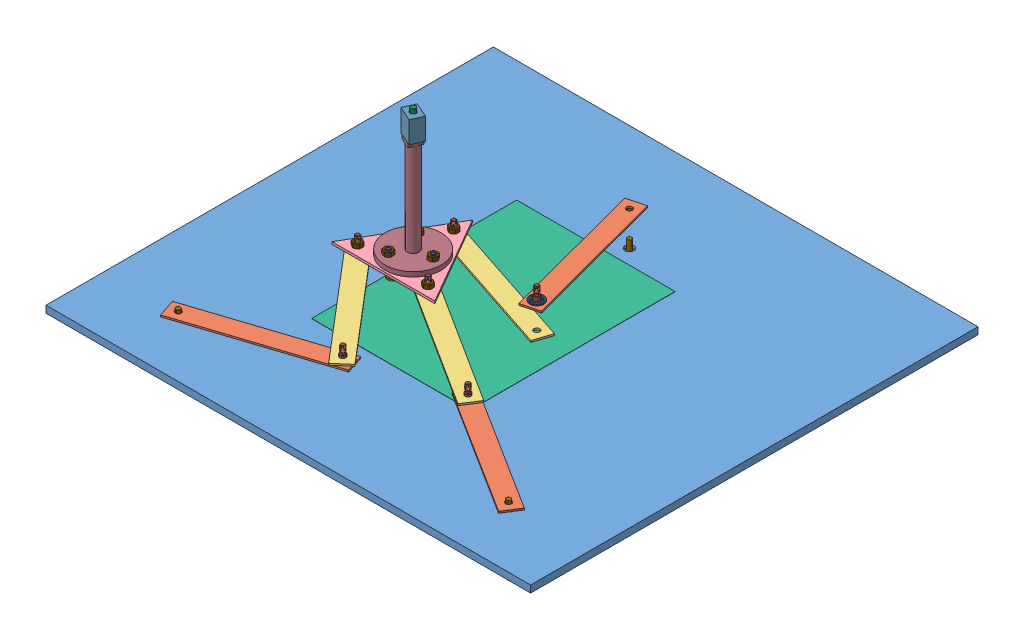
SolidWorks assembly 10_Full_3R_Assembly_rev3, configuration Default. Lengths in mm.
Overall size (660.4 267.78 609.6).
51 component instances, 18 part files, 122 mates.
Components (placement in the parent):
- 01_Base_Plate_rev3-1: 01_Base_Plate_rev3 [Default] at (-311.7855 -6.35 287.7555) size (660.4 9.53 609.6)
- 02_A_Link-1: 02_A_Link [Default] at (-214.7222 8.3926 228.6505) x (0.950724 0 -0.310038) z (0.310038 0 0.950724) size (203.2 2.29 25.4)
- 03_B_Link-1: 03_B_Link [Default] at (-19.6437 12.663 158.9505) x (-0.648292 0 -0.761391) z (0.761391 0 -0.648292) size (203.2 2.29 25.4)
- 02_A_Link-2: 02_A_Link [Default] at (75.596 8.3926 121.5978) x (0.84532 0 0.53426) z (-0.53426 0 0.84532) size (203.2 2.29 25.4)
- 03_B_Link-2: 03_B_Link [Default] at (-74.3873 12.663 26.0288) x (0.843475 0 0.537169) z (-0.537169 0 0.843475) size (203.2 2.29 25.4)
- 02_A_Link-3: 02_A_Link [Default] at (27.4339 49.9469 -192.6042) x (0.25639 0 0.966573) z (0.966573 0 -0.25639) size (203.2 2.29 25.4)
- 03_B_Link-3: 03_B_Link [Default] at (-120.8748 12.663 -52.8875) x (0.949572 0 0.31355) z (-0.31355 0 0.949572) size (203.2 2.29 25.4)
- 04_Platform-1: 04_Platform [Default] at (-174.8101 16.9333 34.8387) size (139.95 3.17 121.2)
- 05_Pen-1: 05_Pen [Default] at (-104.8331 21.9604 -5.5625) x (-0.946735 0 0.322013) z (-0.322013 0 -0.946735) size (12.7 123.83 12.7)
- 06_Paper-1: 06_Paper [Default] at (-114.9356 3.175 122.6553) size (215.9 0.25 279.4)
- 10_Ball_Transfer-1: 10_Ball_Transfer [Default] at (-100.4832 13.2803 -30.5665) x (0.999999 0 0.001404) z (0.001404 0 -0.999999) size (14.51 13.76 14.51)
  - 09_Ball_Holder-1: 09_Ball_Holder [Default] at (19.6556 -3.653 -11.1258) size (14.51 9.53 14.51)
  - 08_Ball-1: 08_Ball [Default] at (19.6556 5.872 -11.1258) size (8.47 8.47 8.47)
- 10_Ball_Transfer-2: 10_Ball_Transfer [Default] at (-82.2518 13.2803 22.5984) x (-0.880102 0 0.474785) z (0.474785 0 0.880102) size (14.51 13.76 14.51)
  - 09_Ball_Holder-1: 09_Ball_Holder [Default] at (19.6556 -3.653 -11.1258) size (14.51 9.53 14.51)
  - 08_Ball-1: 08_Ball [Default] at (19.6556 5.872 -11.1258) size (8.47 8.47 8.47)
- 10_Ball_Transfer-3: 10_Ball_Transfer [Default] at (-148.0473 13.5343 -31.2689) x (0.999295 0 0.037538) z (0.037538 0 -0.999295) size (14.51 13.76 14.51)
  - 09_Ball_Holder-1: 09_Ball_Holder [Default] at (19.6556 -3.653 -11.1258) size (14.51 9.53 14.51)
  - 08_Ball-1: 08_Ball [Default] at (19.6556 5.872 -11.1258) size (8.47 8.47 8.47)
- 07_Motor_rev2-1: 07_Motor_rev2 [Default] at (14.4968 -74.05 -182.8736) x (0 -1 0) z (-0.828709 0 0.559679) size (88.7 37 37)
- 07_Motor_rev2-2: 07_Motor_rev2 [Default] at (-213.4691 -74.05 211.368) x (0 -1 0) z (-0.181552 0 0.983381) size (88.7 37 37)
- 07_Motor_rev2-3: 07_Motor_rev2 [Default] at (250.3675 -74.05 211.8284) x (0 -1 0) z (-0.115781 0 -0.993275) size (88.7 37 37)
- 5909K24_Needle-Roller Thrust Bearing-1: 5909K24_Needle-Roller Thrust Bearing [5909K24] at (64.0007 50.9391 -5.2159) x (-0.973754 0 -0.227603) z (0.227603 0 -0.973754) size (19.05 1.98 19.05)
- 91259A576_Alloy Steel Shoulder Screw-1: 91259A576_Alloy Steel Shoulder Screw [91259A576] at (64.0007 42.1046 -5.2159) x (0.154475 0 0.987997) z (0 -1 0) size (11.11 11.11 26.95)
- 5909K24_Needle-Roller Thrust Bearing-3: 5909K24_Needle-Roller Thrust Bearing [5909K24] at (-37.5467 11.6708 157.5141) x (0.9423 0 0.334769) z (-0.334769 0 0.9423) size (19.05 1.98 19.05)
- 5909K24_Needle-Roller Thrust Bearing-4: 5909K24_Needle-Roller Thrust Bearing [5909K24] at (93.1166 11.6708 117.6473) x (0.999962 0 -0.008701) z (0.008701 0 0.999962) size (19.05 1.98 19.05)
- 91259A576_Alloy Steel Shoulder Screw-2: 91259A576_Alloy Steel Shoulder Screw [91259A576] at (-37.5467 2.8363 157.5141) x (0.890655 0 -0.45468) z (0 -1 0) size (11.11 11.11 26.95)
- 91259A576_Alloy Steel Shoulder Screw-3: 91259A576_Alloy Steel Shoulder Screw [91259A576] at (93.1166 2.8363 117.6473) x (0.621536 0 -0.783386) z (0 -1 0) size (11.11 11.11 26.95)
- 91259A576_Alloy Steel Shoulder Screw-4: 91259A576_Alloy Steel Shoulder Screw [91259A576] at (-152.8131 7.1067 22.1387) x (-0.287715 0 -0.957716) z (0 -1 0) size (11.11 11.11 26.95)
- 91259A576_Alloy Steel Shoulder Screw-5: 91259A576_Alloy Steel Shoulder Screw [91259A576] at (-56.8532 7.1067 22.1387) x (0.554326 0 -0.8323) z (0 -1 0) size (11.11 11.11 26.95)
- 91259A576_Alloy Steel Shoulder Screw-6: 91259A576_Alloy Steel Shoulder Screw [91259A576] at (-104.8331 7.1067 -60.965) x (0.999981 0 0.006147) z (0 -1 0) size (11.11 11.11 26.95)
- 5909K24_Needle-Roller Thrust Bearing-5: 5909K24_Needle-Roller Thrust Bearing [5909K24] at (-152.8131 15.9411 22.1387) x (0.997045 0 0.076824) z (-0.076824 0 0.997045) size (19.05 1.98 19.05)
- 5909K24_Needle-Roller Thrust Bearing-6: 5909K24_Needle-Roller Thrust Bearing [5909K24] at (-104.8331 15.9411 -60.965) x (0.994154 0 -0.107968) z (0.107968 0 0.994154) size (19.05 1.98 19.05)
- 5909K24_Needle-Roller Thrust Bearing-7: 5909K24_Needle-Roller Thrust Bearing [5909K24] at (-56.8532 15.9411 22.1387) x (0.969179 0 -0.246358) z (0.246358 0 0.969179) size (19.05 1.98 19.05)
- 6056N14_Carbon Steel Set Screw Collar-1: 6056N14_Carbon Steel Set Screw Collar [6056N14] at (-206.5855 4.3926 212.6388) x (-0.584369 0 0.811488) z (0 1 0) size (12 12.47 8)
- 6056N14_Carbon Steel Set Screw Collar-2: 6056N14_Carbon Steel Set Screw Collar [6056N14] at (18.4145 43.6609 -177.0726) x (0.948137 0 -0.317863) z (0 1 0) size (12 12.47 8)
- 6056N14_Carbon Steel Set Screw Collar-3: 6056N14_Carbon Steel Set Screw Collar [6056N14] at (243.4145 4.3926 212.6388) x (0.999426 0 0.033886) z (0 -1 0) size (12 12.47 8)
- PenHolder-1: PenHolder [Default] at (-104.8331 20.1083 -5.5625) x (-0.407207 0 0.913336) z (-0.913336 0 -0.407207) size (76.2 138.35 76.2)
- SolenoidAssembly-1: SolenoidAssembly [Default] at (-66.5015 141.5889 -4.966) x (-0.407207 0 0.913336) z (-0.913336 0 -0.407207) size (17 55.9 22)
  - Solenoid_Mount-2: Solenoid_Mount [Default] at (6.5641 46.5695 46.2525) x (1 0 0) z (0 0 -1) size (17 29.7 22)
  - Solenoid_Shaft-1: Solenoid_Shaft [Default] at (15.0641 0.2373 35.2525) x (-0.773677 0 0.63358) z (-0.63358 0 -0.773677) size (6.9 51.9 6.9)
  - Solenoid_Cap-1: Solenoid_Cap [Default] at (15.0641 -3.7627 35.2525) x (0.200587 0 -0.979676) z (0.979676 0 0.200587) size (5 12 5)
- 90604A539_Pan Head Combination Phillips Slotted Screws-1: 90604A539_Pan Head Combination Phillips Slotted Screws [90604A539] at (-119.336 32.8083 -26.415) x (-0.886591 0 -0.462554) z (0 -1 0) size (12.5 12.5 20.66)
- 90604A539_Pan Head Combination Phillips Slotted Screws-2: 90604A539_Pan Head Combination Phillips Slotted Screws [90604A539] at (-115.6405 32.8083 17.4236) x (0.746863 0 0.664978) z (0 -1 0) size (12.5 12.5 20.66)
- 90604A539_Pan Head Combination Phillips Slotted Screws-3: 90604A539_Pan Head Combination Phillips Slotted Screws [90604A539] at (-79.5229 32.8083 -7.696) x (1 0 0) z (0 -1 0) size (12.5 12.5 20.66)
- 95462A029_Medium-Strength Steel Hex Nut-1: 95462A029_Medium-Strength Steel Hex Nut [95462A029] at (-79.5229 29.2365 -7.696) x (-0.145713 0 -0.989327) z (0 -1 0) size (11.11 12.83 6.51)
- 95462A029_Medium-Strength Steel Hex Nut-2: 95462A029_Medium-Strength Steel Hex Nut [95462A029] at (-56.8532 22.8865 22.1387) x (-1 0 0) z (0 1 0) size (11.11 12.83 6.51)
- 95462A029_Medium-Strength Steel Hex Nut-3: 95462A029_Medium-Strength Steel Hex Nut [95462A029] at (-119.336 29.2365 -26.415) x (-1 0 0) z (0 1 0) size (11.11 12.83 6.51)
- 95462A029_Medium-Strength Steel Hex Nut-4: 95462A029_Medium-Strength Steel Hex Nut [95462A029] at (-152.8131 22.8865 22.1387) x (-1 0 0) z (0 1 0) size (11.11 12.83 6.51)
- 95462A029_Medium-Strength Steel Hex Nut-5: 95462A029_Medium-Strength Steel Hex Nut [95462A029] at (-104.8331 22.8865 -60.965) x (-1 0 0) z (0 1 0) size (11.11 12.83 6.51)
- 95462A029_Medium-Strength Steel Hex Nut-6: 95462A029_Medium-Strength Steel Hex Nut [95462A029] at (-115.6405 29.2365 17.4236) x (-0.377684 0 0.925934) z (0 -1 0) size (11.11 12.83 6.51)
Mates (geometry in assembly coordinates):
- Concentric4: concentric anti-aligned: circle of 04_Platform-1; circle of 05_Pen-1
- Coincident21: coincident anti-aligned: plane of 01_Base_Plate_rev3-1 through (-311.7855 3.175 287.7555) normal (0 1 0); plane of 06_Paper-1 through (-114.9356 3.175 122.6553) normal (0 -1 0)
- Distance1: distance = 196.85 mm: line of 06_Paper-1 through (-114.9356 3.429 -156.7447) axis (0 0 1); line of 01_Base_Plate_rev3-1 through (-311.7855 3.175 -321.8445) axis (0 0 1)
- Distance2: distance = 165.1 mm: line of 06_Paper-1 through (100.9644 3.429 -156.7447) axis (-1 0 0); line of 01_Base_Plate_rev3-1 through (348.6145 3.175 -321.8445) axis (-1 0 0)
- Tangent1: tangent anti-aligned: plane of 06_Paper-1 through (-114.9356 3.429 122.6553) normal (0 1 0); sphere of 08_Roller-1
- Tangent2: tangent anti-aligned: plane of 06_Paper-1 through (-114.9356 3.429 122.6553) normal (0 1 0); sphere of 08_Roller-2
- Tangent3: tangent anti-aligned: plane of 06_Paper-1 through (-114.9356 3.429 122.6553) normal (0 1 0); sphere of 08_Roller-3
- Tangent4: tangent anti-aligned: plane of 04_Platform-1 through (-174.8101 16.9333 34.8387) normal (0 -1 0); sphere of 08_Roller-1
- Coincident37: coincident anti-aligned: plane of 02_A_Link-3 through (27.4339 47.6609 -192.6042) normal (0 -1 0); plane of 07_Motor-3 through (15.6523 48.5738 -175.9022) normal (0 1 0)
- Concentric8: concentric aligned: circle of 02_A_Link-3; circle of 07_Motor-3
- Parallel3: parallel aligned: plane of 01_Base_Plate_rev3-1 through (-311.7855 3.175 287.7555) normal (0 0 1); plane of 04_Platform-1 through (-174.8101 20.1083 34.8387) normal (0 0 1)
- Concentric10: concentric anti-aligned: circle of 04_Platform-1; circle of 10_Ball_Transfer-1/09_Ball_Holder-1
- Concentric11: concentric anti-aligned: circle of 04_Platform-1; circle of 10_Ball_Transfer-3/09_Ball_Holder-1
- Concentric12: concentric anti-aligned: circle of 04_Platform-1; circle of 10_Ball_Transfer-2/09_Ball_Holder-1
- Concentric23: concentric anti-aligned: circle of 02_A_Link-1; circle of 07_Motor_rev2-2
- Concentric24: concentric anti-aligned: circle of 02_A_Link-2; circle of 07_Motor_rev2-3
- Concentric25: concentric aligned: circle of 02_A_Link-3; circle of 07_Motor_rev2-1
- Tangent5: tangent anti-aligned: plane of 01_Base_Plate_rev3-1 through (-311.7855 3.175 287.7555) normal (0 1 0); sphere of 10_Ball_Transfer-1/08_Ball-1
- Coincident51: coincident anti-aligned: plane of 01_Base_Plate_rev3-1 through (-311.7855 -6.35 287.7555) normal (0 -1 0); plane of Motor_Mount-1 through (2.2171 -6.35 -164.284) normal (0 1 0)
- Concentric26: concentric anti-aligned: cylinder of 07_Motor_rev2-1 through (14.4968 6.0614 -182.8736) axis (0 1 0) radius 18.5; cylinder of Motor_Mount-1 through (18.4145 -100.9975 -177.0726) axis (0 -1 0) radius 20.6375
- Concentric29: concentric aligned: cylinder of 03_B_Link-3 through (64.0007 12.663 -5.2159) axis (0 1 0) radius 3.9688; cylinder of 91259A427_Alloy Steel Shoulder Screw-1 through (-164.7374 27.7812 -154.398) axis (0 1 0) radius 3.9688
- Concentric30: concentric aligned: cylinder of 02_A_Link-3 through (64.0007 49.9469 -5.2159) axis (0 -1 0) radius 3.9688; cylinder of 5909K24_Needle-Roller Thrust Bearing-1 through (64.0007 49.9469 -5.2159) axis (0 -1 0) radius 3.9624
- Tangent7: tangent anti-aligned: plane of 02_A_Link-3 through (27.4339 49.9469 -192.6042) normal (0 1 0); cylinder of 5909K24_Needle-Roller Thrust Bearing-1 through (70.4402 50.9391 0.8219) axis (0.729494 0 0.683987) radius 0.9922
- Coincident58: coincident anti-aligned: plane of 07_Motor_rev2-1 through (24.1513 -28.25 -168.5783) normal (0 -1 0); plane of Motor_Mount-1 through (3.4631 -22.225 -165.2677) normal (0 1 0)
- Coincident61: coincident anti-aligned: plane of 01_Base_Plate_rev3-1 through (-311.7855 3.175 287.7555) normal (0 1 0); plane of 91259A427_Alloy Steel Shoulder Screw-1 through (-164.7374 6.35 -154.398) normal (0 -1 0)
- Concentric32: concentric anti-aligned: cylinder of 02_A_Link-3 through (64.0007 49.9469 -5.2159) axis (0 -1 0) radius 3.9688; cylinder of 03_B_Link-3 through (64.0007 12.663 -5.2159) axis (0 1 0) radius 3.9688
- Concentric33: concentric anti-aligned: circle of 03_B_Link-3; circle of 5909K24_Needle-Roller Thrust Bearing-2
- Tangent10: tangent anti-aligned: plane of 5909K24_Needle-Roller Thrust Bearing-1 through (66.1687 51.4352 -14.4909) normal (0 1 0); cylinder of 5909K24_Needle-Roller Thrust Bearing-2 through (-163.8488 16.8055 -163.1804) axis (0.100661 0 -0.994921) radius 0.9922
- Coincident62: coincident anti-aligned: plane of 01_Base_Plate_rev3-1 through (-311.7855 3.175 287.7555) normal (0 1 0); plane of 91259A175_Alloy Steel Shoulder Screw-1 through (-164.7374 6.35 -154.398) normal (0 -1 0)
- Concentric34: concentric aligned: circle of 03_B_Link-3; circle of 91259A175_Alloy Steel Shoulder Screw-1
- Concentric36: concentric aligned: circle of 03_B_Link-3; circle of 91259A576_Alloy Steel Shoulder Screw-1
- Concentric37: concentric aligned: circle of 02_A_Link-2; circle of 03_B_Link-2
- Concentric38: concentric aligned: circle of 02_A_Link-1; circle of 03_B_Link-1
- Concentric39: concentric anti-aligned: cylinder of 02_A_Link-2 through (93.1166 8.3926 117.6473) axis (0 1 0) radius 3.9688; cylinder of 5909K24_Needle-Roller Thrust Bearing-4 through (93.1166 10.6786 117.6473) axis (0 -1 0) radius 3.9624
- Tangent13: tangent anti-aligned: plane of 02_A_Link-2 through (75.596 10.6786 121.5978) normal (0 1 0); cylinder of 5909K24_Needle-Roller Thrust Bearing-4 through (89.5966 11.6708 125.7424) axis (-0.398773 0 0.91705) radius 0.9922
- Concentric43: concentric anti-aligned: cylinder of 03_B_Link-1 through (-37.5467 12.663 157.5141) axis (0 1 0) radius 3.9688; cylinder of 5909K24_Needle-Roller Thrust Bearing-3 through (-37.5467 10.6786 157.5141) axis (0 -1 0) radius 3.9624
- Tangent15: tangent anti-aligned: plane of 02_A_Link-1 through (-214.7222 10.6786 228.6505) normal (0 1 0); cylinder of 5909K24_Needle-Roller Thrust Bearing-3 through (-43.2727 11.6708 150.796) axis (-0.648671 0 -0.761069) radius 0.9922
- Concentric44: concentric aligned: cylinder of 03_B_Link-2 through (93.1166 12.663 117.6473) axis (0 1 0) radius 3.9688; cylinder of 91259A576_Alloy Steel Shoulder Screw-3 through (93.1166 29.0301 117.6473) axis (0 1 0) radius 3.9688
- Coincident71: coincident anti-aligned: plane of 02_A_Link-3 through (27.4339 47.6609 -192.6042) normal (0 -1 0); plane of 91259A576_Alloy Steel Shoulder Screw-1 through (69.4903 47.6609 -6.0742) normal (0 1 0)
- Coincident72: coincident anti-aligned: plane of 02_A_Link-2 through (75.596 8.3926 121.5978) normal (0 -1 0); plane of 91259A576_Alloy Steel Shoulder Screw-3 through (88.764 8.3926 114.1939) normal (0 1 0)
- Coincident73: coincident anti-aligned: plane of 02_A_Link-1 through (-214.7222 8.3926 228.6505) normal (0 -1 0); plane of 91259A576_Alloy Steel Shoulder Screw-2 through (-40.073 8.3926 152.5654) normal (0 1 0)
- Concentric45: concentric aligned: cylinder of 02_A_Link-1 through (-37.5467 8.3926 157.5141) axis (0 1 0) radius 3.9688; cylinder of 91259A576_Alloy Steel Shoulder Screw-2 through (-37.5467 29.0301 157.5141) axis (0 1 0) radius 3.9688
- Concentric46: concentric aligned: cylinder of 07_Motor_rev2-2 through (-206.5855 -74.05 212.6388) axis (0 -1 0) radius 3; cylinder of 98541A114_External Retaining Ring-1 through (-200.6826 18.389 208.8764) axis (0 -1 0) radius 2.8
- Coincident74: coincident anti-aligned: plane of 02_A_Link-1 through (-214.7222 8.3926 228.6505) normal (0 -1 0); plane of 98541A114_External Retaining Ring-1 through (-200.6826 18.389 208.8764) normal (0 1 0)
- Concentric49: concentric anti-aligned: cylinder of 03_B_Link-2 through (-56.8532 12.663 22.1387) axis (0 1 0) radius 3.9688; cylinder of 04_Platform-1 through (-56.8532 20.1083 22.1387) axis (0 -1 0) radius 3.9688
- Concentric50: concentric anti-aligned: cylinder of 03_B_Link-1 through (-152.8131 12.663 22.1387) axis (0 1 0) radius 3.9688; cylinder of 04_Platform-1 through (-152.8131 20.1083 22.1387) axis (0 -1 0) radius 3.9688
- Concentric51: concentric anti-aligned: cylinder of 03_B_Link-3 through (-104.8331 12.663 -60.965) axis (0 1 0) radius 3.9688; cylinder of 04_Platform-1 through (-104.8331 20.1083 -60.965) axis (0 -1 0) radius 3.9688
- Coincident77: coincident anti-aligned: plane of 10_Ball_Transfer-1/09_Ball_Holder-1 through (-80.8432 16.9333 -19.4131) normal (0 1 0); plane of Spacer_Platform-1 through (19.8558 20.1083 18.7709) normal (0 -1 0)
- Concentric52: concentric anti-aligned: circle of 10_Ball_Transfer-1/09_Ball_Holder-1; circle of Spacer_Platform-1
- Coincident78: coincident anti-aligned: plane of 04_Platform-1 through (-174.8101 16.9333 34.8387) normal (0 -1 0); plane of Spacer_Platform-1 through (19.8558 28.0458 18.7709) normal (0 1 0)
- Tangent16: tangent anti-aligned: plane of 01_Base_Plate_rev3-1 through (-311.7855 3.175 287.7555) normal (0 1 0); sphere of 10_Ball_Transfer-2/08_Ball-1
- Coincident79: coincident anti-aligned: plane of 10_Ball_Transfer-2/09_Ball_Holder-1 through (-104.8331 16.9333 22.1387) normal (0 1 0); plane of Spacer_Platform-2 through (-4.1341 20.1083 60.3228) normal (0 -1 0)
- Concentric53: concentric anti-aligned: circle of 10_Ball_Transfer-2/09_Ball_Holder-1; circle of Spacer_Platform-2
- Concentric54: concentric anti-aligned: circle of 10_Ball_Transfer-3/09_Ball_Holder-1; circle of Spacer_Platform-3
- Coincident82: coincident anti-aligned: plane of 10_Ball_Transfer-3/09_Ball_Holder-1 through (-128.8231 17.1873 -19.4131) normal (0 1 0); plane of Spacer_Platform-3 through (-28.1241 20.911 18.7709) normal (0 -1 0)
- Parallel4: parallel anti-aligned: plane of 03_B_Link-2 through (-74.3873 14.949 26.0288) normal (0 1 0); plane of 04_Platform-1 through (-174.8101 16.9333 34.8387) normal (0 -1 0)
- Parallel5: parallel aligned: plane of 03_B_Link-1 through (-19.6437 14.949 158.9505) normal (0 1 0); plane of 04_Platform-1 through (-174.8101 20.1083 34.8387) normal (0 1 0)
- Parallel6: parallel aligned: plane of 03_B_Link-3 through (-120.8748 14.949 -52.8875) normal (0 1 0); plane of 04_Platform-1 through (-174.8101 20.1083 34.8387) normal (0 1 0)
- Coincident85: coincident anti-aligned: plane of 03_B_Link-1 through (-19.6437 12.663 158.9505) normal (0 -1 0); plane of 91259A576_Alloy Steel Shoulder Screw-4 through (-158.1344 12.663 23.7374) normal (0 1 0)
- Concentric55: concentric aligned: cylinder of 03_B_Link-1 through (-152.8131 12.663 22.1387) axis (0 1 0) radius 3.9688; cylinder of 91259A576_Alloy Steel Shoulder Screw-4 through (-152.8131 33.3005 22.1387) axis (0 1 0) radius 3.9688
- Concentric56: concentric anti-aligned: cylinder of 91259A576_Alloy Steel Shoulder Screw-4 through (-152.8131 33.3005 22.1387) axis (0 1 0) radius 3.9688; cylinder of 5909K24_Needle-Roller Thrust Bearing-5 through (-152.8131 14.949 22.1387) axis (0 -1 0) radius 3.9624
- Tangent20: tangent anti-aligned: plane of 03_B_Link-1 through (-19.6437 14.949 158.9505) normal (0 1 0); cylinder of 5909K24_Needle-Roller Thrust Bearing-5 through (-159.8074 15.9411 27.5239) axis (-0.792354 0 0.610061) radius 0.9922
- Concentric57: concentric anti-aligned: cylinder of 04_Platform-1 through (-56.8532 20.1083 22.1387) axis (0 -1 0) radius 3.9688; cylinder of 91259A576_Alloy Steel Shoulder Screw-5 through (-56.8532 33.3005 22.1387) axis (0 1 0) radius 3.9688
- Coincident86: coincident anti-aligned: plane of 03_B_Link-2 through (-74.3873 12.663 26.0288) normal (0 -1 0); plane of 91259A576_Alloy Steel Shoulder Screw-5 through (-61.4776 12.663 19.0588) normal (0 1 0)
- Concentric58: concentric anti-aligned: cylinder of 04_Platform-1 through (-104.8331 20.1083 -60.965) axis (0 -1 0) radius 3.9688; cylinder of 91259A576_Alloy Steel Shoulder Screw-6 through (-104.8331 33.3005 -60.965) axis (0 1 0) radius 3.9688
- Concentric59: concentric anti-aligned: cylinder of 91259A576_Alloy Steel Shoulder Screw-5 through (-56.8532 33.3005 22.1387) axis (0 1 0) radius 3.9688; cylinder of 5909K24_Needle-Roller Thrust Bearing-7 through (-56.8532 14.949 22.1387) axis (0 -1 0) radius 3.9624
- Tangent24: tangent anti-aligned: plane of 03_B_Link-2 through (-74.3873 14.949 26.0288) normal (0 1 0); cylinder of 5909K24_Needle-Roller Thrust Bearing-7 through (-54.6785 15.9411 30.694) axis (0.246358 0 0.969179) radius 0.9922
- Concentric60: concentric anti-aligned: cylinder of 91259A576_Alloy Steel Shoulder Screw-6 through (-104.8331 33.3005 -60.965) axis (0 1 0) radius 3.9688; cylinder of 5909K24_Needle-Roller Thrust Bearing-6 through (-104.8331 14.949 -60.965) axis (0 -1 0) radius 3.9624
- Tangent25: tangent anti-aligned: plane of 03_B_Link-3 through (-120.8748 14.949 -52.8875) normal (0 1 0); cylinder of 5909K24_Needle-Roller Thrust Bearing-6 through (-96.2051 15.9411 -62.8301) axis (0.977423 0 -0.211294) radius 0.9922
- Coincident88: coincident anti-aligned: plane of 03_B_Link-3 through (-120.8748 12.663 -52.8875) normal (0 -1 0); plane of 91259A576_Alloy Steel Shoulder Screw-6 through (-104.799 12.663 -66.5211) normal (0 1 0)
- Concentric61: concentric anti-aligned: cylinder of 07_Motor_rev2-1 through (18.4145 -74.05 -177.0726) axis (0 -1 0) radius 3; cylinder of grainger-2alx5-1 through (24.5848 9.389 -180.3783) axis (0 1 0) radius 1.5
- Coincident89: coincident anti-aligned: plane of 02_A_Link-3 through (27.4339 47.6609 -192.6042) normal (0 -1 0); plane of grainger-2alx5-1 through (24.5848 18.389 -180.3783) normal (0 1 0)
- Concentric62: concentric anti-aligned: cylinder of 07_Motor_rev2-3 through (243.4145 -74.05 212.6388) axis (0 -1 0) radius 3; cylinder of grainger-2alx5-2 through (238.4578 9.389 207.6961) axis (0 1 0) radius 1.5
- Coincident90: coincident anti-aligned: plane of 02_A_Link-2 through (75.596 8.3926 121.5978) normal (0 -1 0); plane of grainger-2alx5-2 through (238.4578 18.389 207.6961) normal (0 1 0)
- Concentric63: concentric anti-aligned: cylinder of 07_Motor_rev2-2 through (-206.5855 -74.05 212.6388) axis (0 -1 0) radius 3; cylinder of grainger-2alx5-3 through (-199.783 9.389 210.9877) axis (0 1 0) radius 1.5
- Coincident91: coincident anti-aligned: plane of 02_A_Link-1 through (-214.7222 8.3926 228.6505) normal (0 -1 0); plane of grainger-2alx5-3 through (-199.783 18.389 210.9877) normal (0 1 0)
- Concentric64: concentric aligned: cylinder of 07_Motor_rev2-2 through (-206.5855 -74.05 212.6388) axis (0 -1 0) radius 3; cylinder of 6056N14_Carbon Steel Set Screw Collar-1 through (-206.5855 8.3926 212.6388) axis (0 -1 0) radius 3
- Coincident92: coincident anti-aligned: plane of 02_A_Link-1 through (-214.7222 8.3926 228.6505) normal (0 -1 0); plane of 6056N14_Carbon Steel Set Screw Collar-1 through (-206.5855 8.3926 212.6388) normal (0 1 0)
- Concentric65: concentric anti-aligned: cylinder of 07_Motor_rev2-3 through (243.4145 -74.05 212.6388) axis (0 -1 0) radius 3; cylinder of 6056N14_Carbon Steel Set Screw Collar-3 through (243.4145 0.3926 212.6388) axis (0 1 0) radius 3
- Coincident93: coincident anti-aligned: plane of 02_A_Link-2 through (75.596 8.3926 121.5978) normal (0 -1 0); plane of 6056N14_Carbon Steel Set Screw Collar-3 through (243.4145 8.3926 212.6388) normal (0 1 0)
- Concentric66: concentric aligned: cylinder of 07_Motor_rev2-1 through (18.4145 -74.05 -177.0726) axis (0 -1 0) radius 3; cylinder of 6056N14_Carbon Steel Set Screw Collar-2 through (18.4145 47.6609 -177.0726) axis (0 -1 0) radius 3
- Coincident94: coincident anti-aligned: plane of 02_A_Link-3 through (27.4339 47.6609 -192.6042) normal (0 -1 0); plane of 6056N14_Carbon Steel Set Screw Collar-2 through (18.4145 47.6609 -177.0726) normal (0 1 0)
- Coincident95: coincident anti-aligned: plane of 10_Ball_Transfer-3/09_Ball_Holder-1 through (-128.8231 17.1873 -19.4131) normal (0 1 0); plane of 92510A763_Aluminum Unthreaded Spacer-1 through (-8.7932 17.1873 -129.4012) normal (0 -1 0)
- Concentric67: concentric aligned: circle of 10_Ball_Transfer-3/09_Ball_Holder-1; circle of 92510A763_Aluminum Unthreaded Spacer-1
- Tangent26: tangent anti-aligned: plane of 06_Paper-1 through (-114.9356 3.429 122.6553) normal (0 1 0); sphere of 10_Ball_Transfer-3/08_Ball-1
- Coincident97: coincident anti-aligned: plane of 04_Platform-1 through (-174.8101 16.9333 34.8387) normal (0 -1 0); plane of 92510A763_Aluminum Unthreaded Spacer-1 through (-8.7932 25.1248 -129.4012) normal (0 1 0)
- Coincident98: coincident aligned: circle of 10_Ball_Transfer-2/09_Ball_Holder-1; circle of 92510A763_Aluminum Unthreaded Spacer-2
- Coincident99: coincident anti-aligned: plane of 10_Ball_Transfer-1/09_Ball_Holder-1 through (-80.8432 16.9333 -19.4131) normal (0 1 0); plane of 92510A763_Aluminum Unthreaded Spacer-3 through (37.2403 16.9333 -130.0033) normal (0 -1 0)
- Coincident100: coincident aligned: circle of 10_Ball_Transfer-1/09_Ball_Holder-1; circle of 92510A763_Aluminum Unthreaded Spacer-3
- Concentric68: concentric aligned: cylinder of 05_Pen-1 through (-104.8331 21.9604 -5.5625) axis (0 -1 0) radius 6.35; cylinder of PenHolder-1 through (-104.8331 173.6639 -5.5625) axis (0 -1 0) radius 7.1437
- Coincident101: coincident anti-aligned: plane of 04_Platform-1 through (-174.8101 20.1083 34.8387) normal (0 1 0); plane of PenHolder-1 through (-104.8331 20.1083 -5.5625) normal (0 -1 0)
- Concentric69: concentric aligned: cylinder of PenHolder-1 through (-104.8331 20.1083 -5.5625) axis (0 1 0) radius 3; cylinder of SolenoidAssembly-1/Solenoid_Cap-1 through (-104.8331 258.6007 -5.5625) axis (0 1 0) radius 2.5
- Coincident102: coincident anti-aligned: plane of PenHolder-1 through (-104.8331 158.4583 -5.5625) normal (0 1 0); plane of SolenoidAssembly-1/Solenoid_Mount-2 through (-91.3252 158.4583 -8.8466) normal (0 -1 0)
- Concentric70: concentric anti-aligned: circle of PenHolder-1; circle of 90604A539_Pan Head Combination Phillips Slotted Screws-1
- Coincident103: coincident anti-aligned: plane of 04_Platform-1 through (-174.8101 16.9333 34.8387) normal (0 -1 0); plane of 90604A539_Pan Head Combination Phillips Slotted Screws-1 through (-121.8561 16.9333 -21.5846) normal (0 1 0)
- Concentric71: concentric anti-aligned: circle of PenHolder-1; circle of 90604A539_Pan Head Combination Phillips Slotted Screws-2
- Coincident104: coincident anti-aligned: plane of 04_Platform-1 through (-174.8101 16.9333 34.8387) normal (0 -1 0); plane of 90604A539_Pan Head Combination Phillips Slotted Screws-2 through (-112.0175 16.9333 13.3545) normal (0 1 0)
- Concentric72: concentric anti-aligned: circle of PenHolder-1; circle of 90604A539_Pan Head Combination Phillips Slotted Screws-3
- Coincident105: coincident anti-aligned: plane of 04_Platform-1 through (-174.8101 16.9333 34.8387) normal (0 -1 0); plane of 90604A539_Pan Head Combination Phillips Slotted Screws-3 through (-79.5229 16.9333 -13.1443) normal (0 1 0)
- Coincident106: coincident anti-aligned: plane of PenHolder-1 through (-120.3477 26.4583 29.2356) normal (0 1 0); plane of 95462A029_Medium-Strength Steel Hex Nut-1 through (-75.5396 26.4583 -2.6665) normal (0 -1 0)
- Concentric73: concentric anti-aligned: circle of 90604A539_Pan Head Combination Phillips Slotted Screws-3; circle of 95462A029_Medium-Strength Steel Hex Nut-1
- Concentric74: concentric aligned: circle of 90604A539_Pan Head Combination Phillips Slotted Screws-1; circle of 95462A029_Medium-Strength Steel Hex Nut-3
- Coincident109: coincident anti-aligned: plane of PenHolder-1 through (-120.3477 26.4583 29.2356) normal (0 1 0); plane of 95462A029_Medium-Strength Steel Hex Nut-3 through (-113.7797 26.4583 -23.2071) normal (0 -1 0)
- Concentric75: concentric aligned: circle of 91259A576_Alloy Steel Shoulder Screw-5; circle of 95462A029_Medium-Strength Steel Hex Nut-2
- Coincident110: coincident anti-aligned: plane of 04_Platform-1 through (-174.8101 20.1083 34.8387) normal (0 1 0); plane of 95462A029_Medium-Strength Steel Hex Nut-2 through (-51.2969 20.1083 25.3466) normal (0 -1 0)
- Concentric76: concentric aligned: circle of 91259A576_Alloy Steel Shoulder Screw-4; circle of 95462A029_Medium-Strength Steel Hex Nut-4
- Coincident112: coincident anti-aligned: plane of 04_Platform-1 through (-174.8101 20.1083 34.8387) normal (0 1 0); plane of 95462A029_Medium-Strength Steel Hex Nut-4 through (-147.2568 20.1083 25.3466) normal (0 -1 0)
- Concentric77: concentric aligned: circle of 91259A576_Alloy Steel Shoulder Screw-6; circle of 95462A029_Medium-Strength Steel Hex Nut-5
- Coincident113: coincident anti-aligned: plane of 04_Platform-1 through (-174.8101 20.1083 34.8387) normal (0 1 0); plane of 95462A029_Medium-Strength Steel Hex Nut-5 through (-99.2769 20.1083 -57.7571) normal (0 -1 0)
- Coincident114: coincident anti-aligned: plane of PenHolder-1 through (-120.3477 26.4583 29.2356) normal (0 1 0); plane of 95462A029_Medium-Strength Steel Hex Nut-6 through (-116.5123 26.4583 11.0673) normal (0 -1 0)
- Concentric78: concentric anti-aligned: circle of 90604A539_Pan Head Combination Phillips Slotted Screws-2; circle of 95462A029_Medium-Strength Steel Hex Nut-6
- Parallel8: parallel aligned: line of PenHolder-1 through (-94.5218 158.4583 -10.2718) axis (-0.913336 0 -0.407207); line of SolenoidAssembly-1/Solenoid_Mount-2 through (-91.3252 158.4583 -8.8466) axis (-0.913336 0 -0.407207)
- Tangent28: tangent anti-aligned: plane of 04_Platform-1 through (-174.8101 16.9333 34.8387) normal (0 -1 0); cylinder of 5909K24_Needle-Roller Thrust Bearing-5 through (-149.8528 15.9411 30.4549) axis (0.335352 0 0.942093) radius 0.9922
- Tangent29: tangent anti-aligned: plane of 04_Platform-1 through (-174.8101 16.9333 34.8387) normal (0 -1 0); cylinder of 5909K24_Needle-Roller Thrust Bearing-7 through (-49.0403 15.9411 26.2472) axis (0.885086 0 0.465428) radius 0.9922
- Concentric79: concentric anti-aligned: circle of 01_Base_Plate_rev3-1; circle of 07_Motor_rev2-2
- Concentric80: concentric anti-aligned: circle of 01_Base_Plate_rev3-1; circle of 07_Motor_rev2-3
- Concentric81: concentric anti-aligned: circle of 01_Base_Plate_rev3-1; circle of 07_Motor_rev2-1
- Coincident115: coincident anti-aligned: plane of 01_Base_Plate_rev3-1 through (-311.7855 -6.35 287.7555) normal (0 -1 0); plane of 07_Motor_rev2-2 through (-195.2766 -6.35 214.7267) normal (0 1 0)
- Coincident116: coincident anti-aligned: plane of 04_Platform-1 through (-174.8101 16.9333 34.8387) normal (0 -1 0); plane of 10_Ball_Transfer-1/09_Ball_Holder-1 through (-80.8432 16.9333 -19.4131) normal (0 1 0)
- Coincident117: coincident anti-aligned: plane of 01_Base_Plate_rev3-1 through (-311.7855 -6.35 287.7555) normal (0 -1 0); plane of 07_Motor_rev2-3 through (231.9919 -6.35 213.9703) normal (0 1 0)
- Coincident118: coincident anti-aligned: plane of 01_Base_Plate_rev3-1 through (-311.7855 -6.35 287.7555) normal (0 -1 0); plane of 07_Motor_rev2-1 through (24.8509 -6.35 -167.5424) normal (0 1 0)
- Tangent30: tangent anti-aligned: plane of 04_Platform-1 through (-174.8101 16.9333 34.8387) normal (0 -1 0); cylinder of 5909K24_Needle-Roller Thrust Bearing-6 through (-97.7097 15.9411 -66.1782) axis (0.806979 0 -0.59058) radius 0.9922
